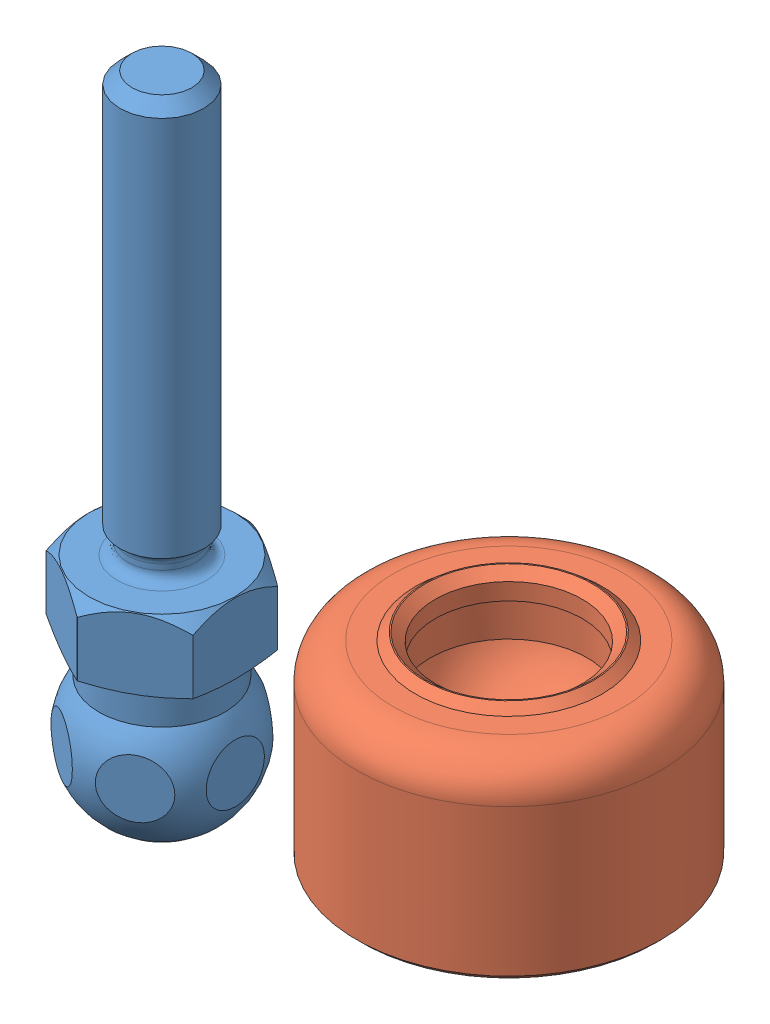
SolidWorks assembly Frame Foot, configuration Default. Lengths in mm.
Overall size (49.13 62.04 29.36).
2 component instances, 2 part files, 3 mates.
Components (placement in the parent):
- 8020-12195-$PARTNUMBER-1: 8020-12195-$PARTNUMBER [Default] x (1 0 0) z (0 0 -1) size (15.06 62.04 17.76)
- 8020-DEFAULT-1: 8020-DEFAULT [Default] at (27.1023 -17.4986 -5.9804) size (29 20.7 29)
Mates (geometry in assembly coordinates):
- Coincident1: coincident anti-aligned: plane of 8020-12195-$PARTNUMBER-1 through (0 0 0) normal (0 0 -1); plane of assembly through (0 0 0) normal (0 0 1)
- Coincident2: coincident anti-aligned: plane of 8020-12195-$PARTNUMBER-1 through (0 0 0) normal (0 -1 0); plane of assembly through (0 0 0) normal (0 1 0)
- Coincident3: coincident aligned: plane of 8020-12195-$PARTNUMBER-1 through (0 0 0) normal (1 0 0); plane of assembly through (0 0 0) normal (1 0 0)
